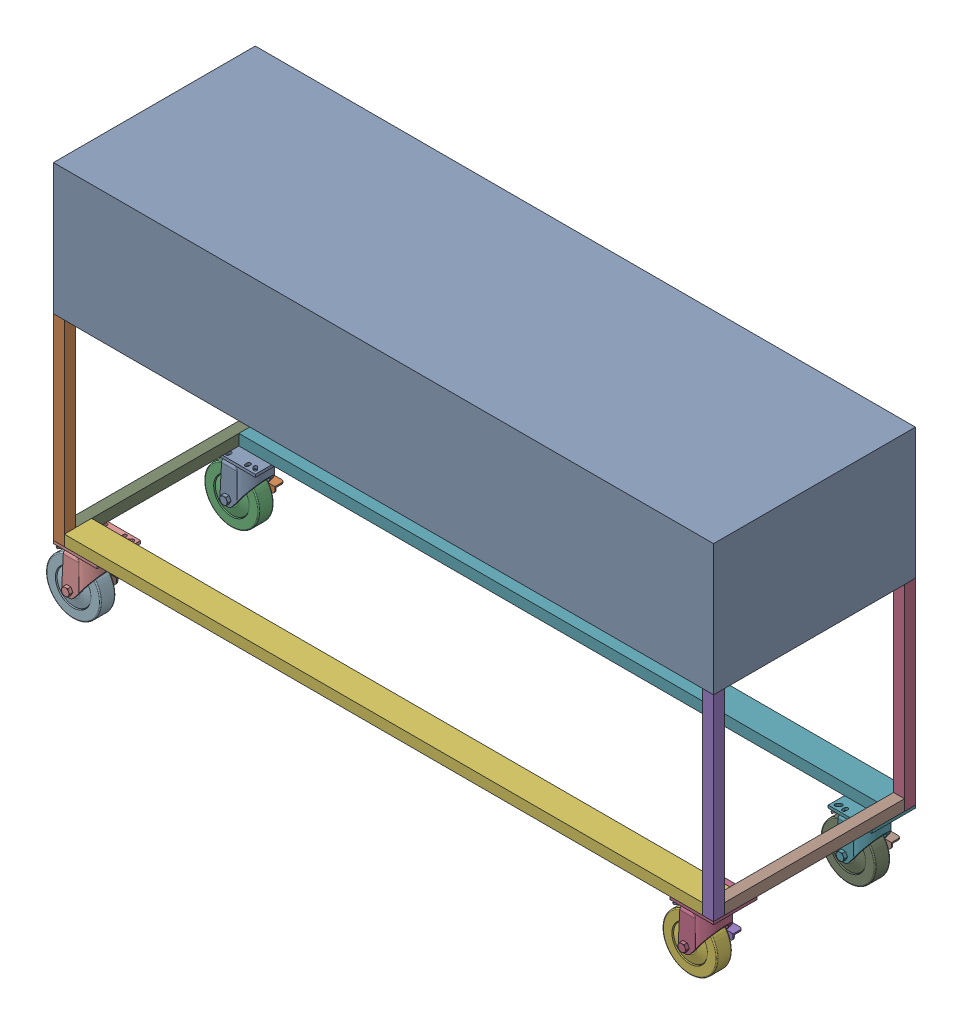
SolidWorks assembly Base Assembly, configuration Default. Lengths in mm.
Overall size (1587.55 930.27 474.36).
13 component instances, 5 part files, 36 mates.
Components (placement in the parent):
- Base-1: Base [Default] at origin size (1536.7 304.8 469.9)
- Base Leg-2: Base Leg [Default] at (0 -304.8 0) size (25.4 457.2 25.4)
- Base Leg-3: Base Leg [Default] at (0 -304.8 -444.5) size (25.4 457.2 25.4)
- Base Leg-4: Base Leg [Default] at (1511.3 -304.8 -444.5) size (25.4 457.2 25.4)
- Base Leg-5: Base Leg [Default] at (1511.3 -304.8 0) size (25.4 457.2 25.4)
- Long Leg Support-3: Long Leg Support [Default] at (25.146 -762 0) size (1486.15 25.4 63.5)
- Long Leg Support-4: Long Leg Support [Default] at (25.146 -762 -406.4) size (1486.15 25.4 63.5)
- Short Leg Support-3: Short Leg Support [Default] at (1536.7 -762 -21.336) x (0 0 -1) z (1 0 0) size (423.16 25.4 25.4)
- Short Leg Support-4: Short Leg Support [Default] at (0 -762 -448.564) x (0 0 1) z (-1 0 0) size (423.16 25.4 25.4)
- Caster Wheels-1: Caster Wheels [28925T74] at (50.75 -762 -50.75) size (152.35 168.28 105.96)
- Caster Wheels-2: Caster Wheels [28925T74] at (50.75 -762 -419.15) size (152.35 168.28 105.96)
- Caster Wheels-3: Caster Wheels [28925T74] at (1485.95 -762 -50.75) size (152.35 168.28 105.96)
- Caster Wheels-4: Caster Wheels [28925T74] at (1485.95 -762 -419.15) size (152.35 168.28 105.96)
Mates (geometry in assembly coordinates):
- Coincident3: coincident anti-aligned: plane of Base-1 through (0 -304.8 0) normal (0 -1 0); plane of Base Leg-2 through (0 -304.8 0) normal (0 1 0)
- Coincident4: coincident aligned: plane of Base-1 through (0 -304.8 0) normal (0 0 1); plane of Base Leg-2 through (0 -762 0) normal (0 0 1)
- Coincident5: coincident aligned: plane of Base-1 through (0 -304.8 0) normal (-1 0 0); plane of Base Leg-2 through (0 -762 0) normal (-1 0 0)
- Coincident6: coincident anti-aligned: plane of Base-1 through (0 -304.8 0) normal (0 -1 0); plane of Base Leg-3 through (0 -304.8 -444.5) normal (0 1 0)
- Coincident7: coincident aligned: plane of Base-1 through (0 -304.8 0) normal (-1 0 0); plane of Base Leg-3 through (0 -762 -444.5) normal (-1 0 0)
- Coincident8: coincident aligned: plane of Base-1 through (0 -304.8 -469.9) normal (0 0 -1); plane of Base Leg-3 through (0 -762 -469.9) normal (0 0 -1)
- Coincident9: coincident anti-aligned: plane of Base-1 through (0 -304.8 0) normal (0 -1 0); plane of Base Leg-4 through (1511.3 -304.8 -444.5) normal (0 1 0)
- Coincident10: coincident aligned: plane of Base-1 through (0 -304.8 -469.9) normal (0 0 -1); plane of Base Leg-4 through (1511.3 -762 -469.9) normal (0 0 -1)
- Coincident11: coincident aligned: plane of Base-1 through (1536.7 -304.8 0) normal (1 0 0); plane of Base Leg-4 through (1536.7 -762 -444.5) normal (1 0 0)
- Coincident12: coincident anti-aligned: plane of Base-1 through (0 -304.8 0) normal (0 -1 0); plane of Base Leg-5 through (1511.3 -304.8 0) normal (0 1 0)
- Coincident13: coincident aligned: plane of Base-1 through (1536.7 -304.8 0) normal (1 0 0); plane of Base Leg-5 through (1536.7 -762 0) normal (1 0 0)
- Coincident14: coincident aligned: plane of Base-1 through (0 -304.8 0) normal (0 0 1); plane of Base Leg-5 through (1511.3 -762 0) normal (0 0 1)
- Coincident29: coincident anti-aligned: plane of Base Leg-5 through (1511.3 -762 0) normal (-1 0 0); plane of Long Leg Support-3 through (1511.3 -762 0) normal (1 0 0)
- Coincident30: coincident aligned: plane of Base Leg-5 through (1511.3 -762 0) normal (0 0 1); plane of Long Leg Support-3 through (1511.3 -762 0) normal (0 0 1)
- Coincident31: coincident aligned: plane of Base Leg-5 through (1511.3 -762 0) normal (0 -1 0); plane of Long Leg Support-3 through (1511.3 -762 0) normal (0 -1 0)
- Coincident32: coincident anti-aligned: plane of Base Leg-4 through (1511.3 -762 -444.5) normal (-1 0 0); plane of Long Leg Support-4 through (1511.3 -762 -406.4) normal (1 0 0)
- Coincident33: coincident aligned: plane of Long Leg Support-4 through (1511.3 -762 -469.9) normal (0 0 -1); plane of Base Leg-4 through (1511.3 -762 -469.9) normal (0 0 -1)
- Coincident34: coincident aligned: plane of Base Leg-4 through (1511.3 -762 -444.5) normal (0 -1 0); plane of Long Leg Support-4 through (1511.3 -762 -406.4) normal (0 -1 0)
- Coincident35: coincident anti-aligned: plane of Base Leg-4 through (1511.3 -762 -444.5) normal (0 0 1); plane of Short Leg Support-3 through (1536.7 -762 -444.5) normal (0 0 -1)
- Coincident36: coincident aligned: plane of Base Leg-4 through (1536.7 -762 -444.5) normal (1 0 0); plane of Short Leg Support-3 through (1536.7 -762 -444.5) normal (1 0 0)
- Coincident37: coincident aligned: plane of Base Leg-5 through (1511.3 -762 0) normal (0 -1 0); plane of Short Leg Support-3 through (1536.7 -762 -444.5) normal (0 -1 0)
- Coincident38: coincident anti-aligned: plane of Base Leg-2 through (0 -762 -25.4) normal (0 0 -1); plane of Short Leg Support-4 through (0 -762 -25.4) normal (0 0 1)
- Coincident39: coincident aligned: plane of Base Leg-2 through (0 -762 0) normal (-1 0 0); plane of Short Leg Support-4 through (0 -762 -25.4) normal (-1 0 0)
- Coincident40: coincident aligned: plane of Base Leg-2 through (0 -762 0) normal (0 -1 0); plane of Short Leg Support-4 through (0 -762 -25.4) normal (0 -1 0)
- Coincident41: coincident: plane of Base Leg-2 through (0 -762 0) normal (0 -1 0); plane of Caster Wheels-1 through (101.5 -762 0) normal (0 1 0)
- Coincident42: coincident: plane of Base Leg-2 through (0 -762 0) normal (0 0 1); plane of Caster Wheels-1 through (0 -768.35 0) normal (0 0 1)
- Coincident43: coincident aligned: plane of Base Leg-2 through (0 -762 0) normal (-1 0 0); plane of Caster Wheels-1 through (0 -768.35 -101.5) normal (-1 0 0)
- Coincident44: coincident: plane of Base Leg-3 through (0 -762 -444.5) normal (0 -1 0); plane of Caster Wheels-2 through (101.5 -762 -368.4) normal (0 1 0)
- Coincident45: coincident: plane of Short Leg Support-4 through (0 -762 -25.4) normal (-1 0 0); plane of Caster Wheels-2 through (0 -768.35 -469.9) normal (-1 0 0)
- Coincident46: coincident aligned: plane of Long Leg Support-4 through (1511.3 -762 -469.9) normal (0 0 -1); plane of Caster Wheels-2 through (0 -768.35 -469.9) normal (0 0 -1)
- Coincident47: coincident: plane of Long Leg Support-3 through (1511.3 -762 0) normal (0 -1 0); plane of Caster Wheels-3 through (1536.7 -762 0) normal (0 1 0)
- Coincident48: coincident: plane of Base Leg-5 through (1511.3 -762 0) normal (0 0 1); plane of Caster Wheels-3 through (1435.2 -768.35 0) normal (0 0 1)
- Coincident49: coincident aligned: plane of Short Leg Support-3 through (1536.7 -762 -444.5) normal (1 0 0); plane of Caster Wheels-3 through (1536.7 -768.35 -101.5) normal (1 0 0)
- Coincident50: coincident: plane of Long Leg Support-4 through (1511.3 -762 -406.4) normal (0 -1 0); plane of Caster Wheels-4 through (1536.7 -762 -368.4) normal (0 1 0)
- Coincident51: coincident: plane of Base Leg-4 through (1511.3 -762 -469.9) normal (0 0 -1); plane of Caster Wheels-4 through (1435.2 -768.35 -469.9) normal (0 0 -1)
- Coincident52: coincident aligned: plane of Short Leg Support-3 through (1536.7 -762 -444.5) normal (1 0 0); plane of Caster Wheels-4 through (1536.7 -768.35 -469.9) normal (1 0 0)
